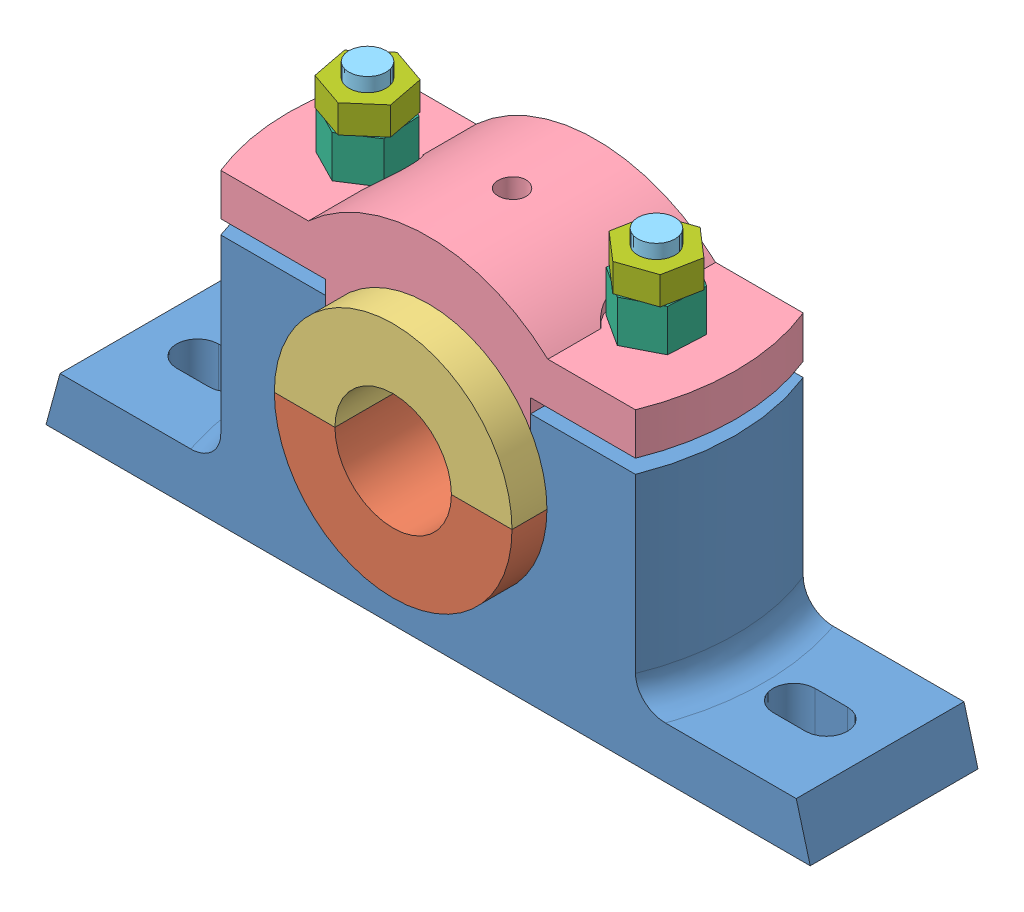
SolidWorks assembly Assem4, configuration Default. Lengths in mm.
Overall size (164 84 51).
11 component instances, 7 part files, 0 mates.
Components (placement in the parent):
- Assem1a-1: Assem1a [Default] at (-7.6159 10.7083 -13.447) size (164 84 51)
  - pp-1-1: pp-1 [Default] at (59.7918 46.6128 134.7692) size (164 54 36)
  - pp-4(1)-2: pp-4(1) [Default] at (59.7918 84.6128 134.7691) x (0 0 -1) z (1 0.000048 0) size (51 25.5 51)
  - pp-3-1: pp-3 [Default] at (59.7918 84.6128 134.7691) x (0 0 -1) z (1 0.000048 0) size (51 25.5 51)
  - pp-2-2: pp-2 [Default] at (59.7918 90.6128 134.7692) size (96 32 36)
  - pp-7-1: pp-7 [Default] at (28.7918 54.6128 134.7692) x (0 1 0) z (0 0 1) size (82 19 19)
  - pp-5(1)-1: pp-5(1) [Default] at (28.7918 117.1128 134.7692) x (1 0 0) z (0 -1 0) size (14.27 16 9)
  - pp-6(1)-1: pp-6(1) [Default] at (28.7918 124.6128 134.7692) x (1 0 0) z (0 -1 0) size (15.12 15.71 6)
  - pp-7-2: pp-7 [Default] at (90.7918 54.6128 134.7692) x (0 1 0) z (0 0 1) size (82 19 19)
  - pp-5(1)-2: pp-5(1) [Default] at (90.7918 117.1128 134.7692) x (1 0 0) z (0 1 0) size (14.27 16 9)
  - pp-6(1)-2: pp-6(1) [Default] at (90.7918 124.6128 134.7692) x (1 0 0) z (0 1 0) size (15.12 15.71 6)
